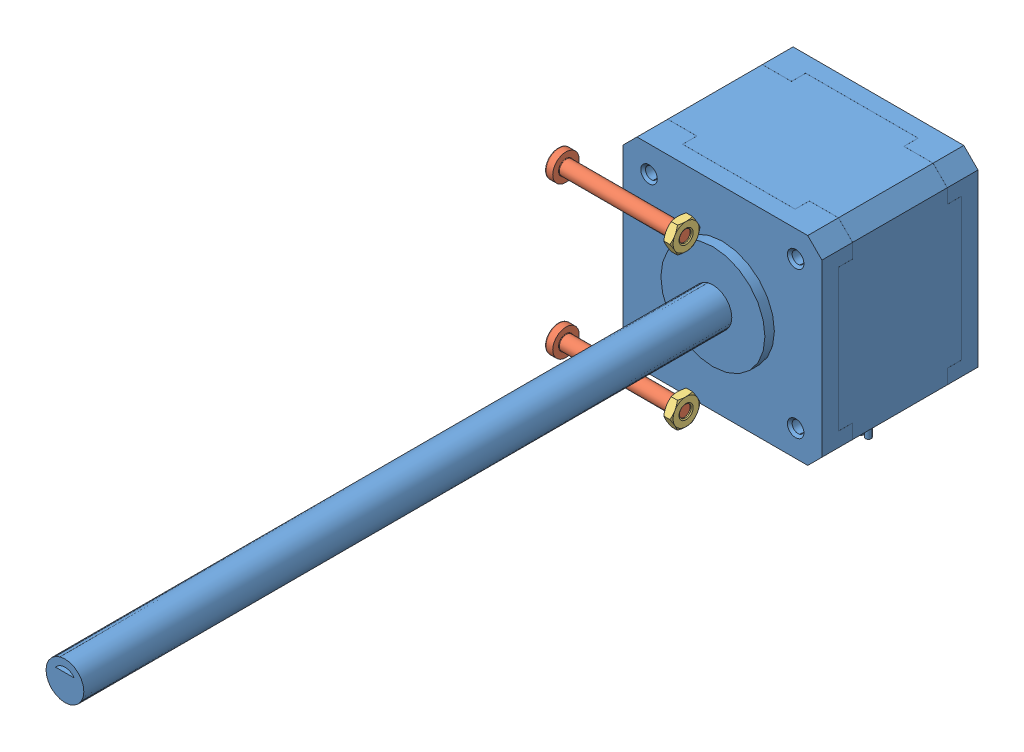
SolidWorks assembly Zmotor, configuration Default. Lengths in mm.
Overall size (48.45 59.12 172).
10 component instances, 5 part files, 12 mates.
Components (placement in the parent):
- Steper Motor 34mm (42HD0401-135L)-1: Steper Motor 34mm (42HD0401-135L) [Default] at origin size (42.1 59.12 172)
- Z Motor mount2-1: Z Motor mount2 [Valor predeterminado] at (-330.7157 -87.3227 33) x (0 1 0) z (0 0 1) size (42.1 43.6 14)
- ISO 7046-1 - M3 x 12 - Z --- 12N-1: ISO 7046-1 - M3 x 12 - Z --- 12N [ISO 7046-1 - M3 x 8 - Z --- 8N] at (-15.5 15.5 37) x (0 0 -1) z (0.999999 0.001551 0) size (8 5.5 5.5)
- ISO 7046-1 - M3 x 12 - Z --- 12N-2: ISO 7046-1 - M3 x 12 - Z --- 12N [ISO 7046-1 - M3 x 8 - Z --- 8N] at (15.5 15.5 37) x (0 0 -1) z (0.444535 0.895762 0) size (8 5.5 5.5)
- ISO 7046-1 - M3 x 12 - Z --- 12N-3: ISO 7046-1 - M3 x 12 - Z --- 12N [ISO 7046-1 - M3 x 8 - Z --- 8N] at (15.5 -15.5 37) x (0 0 -1) z (0.999915 -0.013072 0) size (8 5.5 5.5)
- ISO 7046-1 - M3 x 12 - Z --- 12N-4: ISO 7046-1 - M3 x 12 - Z --- 12N [ISO 7046-1 - M3 x 8 - Z --- 8N] at (-15.5 -15.5 37) x (0 0 -1) z (0.999885 0.015174 0) size (8 5.5 5.5)
- ISO 7045 - M4 x 12 - Z --- 12N-1: ISO 7045 - M4 x 12 - Z --- 12N [ISO 7045 - M3 x 25 - Z --- 25N] at (-27.45 -16.0364 41.0127) x (1 0 0) z (0 -1 0) size (27.35 5.6 5.6)
- ISO 7045 - M4 x 12 - Z --- 12N-2: ISO 7045 - M4 x 12 - Z --- 12N [ISO 7045 - M3 x 25 - Z --- 25N] at (-27.45 16.0364 41.0127) x (1 0 0) z (0 -1 0) size (27.35 5.6 5.6)
- hex thin nut chamfered gradeab_iso2-1: hex thin nut chamfered gradeab_iso2 [Hexagon Thin Nut ISO - 4035 - M3 - N] at (0.35 16.0364 41.0127) x (0 1 0) z (1 0 0) size (5.5 6.35 1.8)
- hex thin nut chamfered gradeab_iso2-2: hex thin nut chamfered gradeab_iso2 [Hexagon Thin Nut ISO - 4035 - M3 - N] at (0.35 -16.0364 41.0127) x (0 1 0) z (1 0 0) size (5.5 6.35 1.8)
Mates (geometry in assembly coordinates):
- Coincidente255: coincident: plane of Steper Motor 34mm (42HD0401-135L)-1 through (21.05 21.05 33) normal (0 0 1); plane of Z Motor mount2-1 through (-330.7157 -87.3227 33) normal (0 0 -1)
- Coincidente256: coincident: plane of Steper Motor 34mm (42HD0401-135L)-1 through (-21.05 21.05 33) normal (0 1 0); plane of Z Motor mount2-1 through (21.05 21.05 37) normal (0 1 0)
- Coincidente258: coincident: plane of Steper Motor 34mm (42HD0401-135L)-1 through (21.05 -21.05 33) normal (1 0 0); plane of Z Motor mount2-1 through (21.05 21.05 37) normal (1 0 0)
- Coincidente259: coincident: cone of Z Motor mount2-1 through (-15.5 15.5 37) axis (0 0 -1); cone of ISO 7046-1 - M3 x 12 - Z --- 12N-1 through (-15.5 15.5 36.6) axis (0 0 -1)
- Coincidente260: coincident: cone of Z Motor mount2-1 through (15.5 15.5 37) axis (0 0 -1); cone of ISO 7046-1 - M3 x 12 - Z --- 12N-2 through (15.5 15.5 36.6) axis (0 0 -1)
- Coincidente261: coincident: cone of Z Motor mount2-1 through (15.5 -15.5 37) axis (0 0 -1); cone of ISO 7046-1 - M3 x 12 - Z --- 12N-3 through (15.5 -15.5 36.6) axis (0 0 -1)
- Coincidente262: coincident: cone of Z Motor mount2-1 through (-15.5 -15.5 37) axis (0 0 -1); cone of ISO 7046-1 - M3 x 12 - Z --- 12N-4 through (-15.5 -15.5 36.6) axis (0 0 -1)
- Concentric45: concentric: cylinder of Z Motor mount2-1 through (-21.05 16.0364 41.0127) axis (-1 0 0) radius 1.6; cylinder of hex thin nut chamfered gradeab_iso2-1 through (-24.6875 16.0364 41.0127) axis (1 0 0) radius 1.5
- Coincident786995: coincident: plane of Z Motor mount2-1 through (-1.45 -87.3227 33) normal (1 0 0); plane of hex thin nut chamfered gradeab_iso2-1 through (-1.45 16.0364 44.1881) normal (-1 0 0)
- Concentric46: concentric: cylinder of Z Motor mount2-1 through (-21.05 -16.0364 41.0127) axis (-1 0 0) radius 1.6; cylinder of hex thin nut chamfered gradeab_iso2-2 through (-24.6875 -16.0364 41.0127) axis (1 0 0) radius 1.5
- Coincident786996: coincident: plane of Z Motor mount2-1 through (-1.45 -87.3227 33) normal (1 0 0); plane of hex thin nut chamfered gradeab_iso2-2 through (-1.45 -16.0364 44.1881) normal (-1 0 0)
- Concentric56: concentric: cylinder of Z Motor mount2-1 through (-21.05 16.0364 41.0127) axis (-1 0 0) radius 1.6; cylinder of ISO 7045 - M4 x 12 - Z --- 12N-2 through (-52.85 16.0364 41.0127) axis (-1 0 0) radius 1.5
